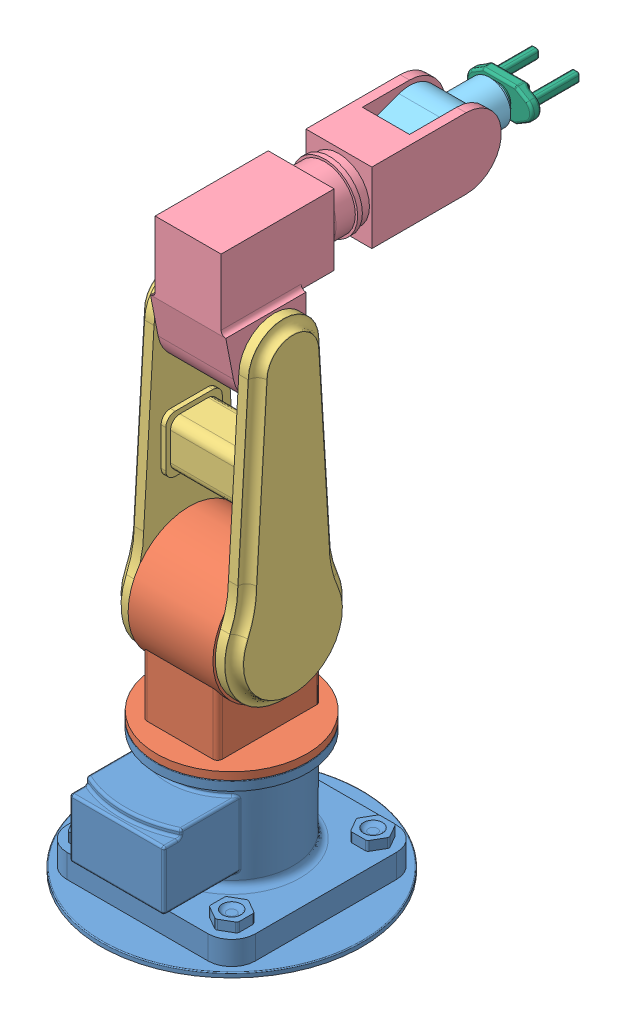
SolidWorks assembly 4DOFmanipulator, configuration 默认. Lengths in mm.
Overall size (555 1216 964.96).
6 component instances, 6 part files, 15 mates.
Components (placement in the parent):
- Base-2: Base [默认] at origin size (555 280 555)
- Link 1-1: Link 1 [默认] at (0 160 0) x (0 0 1) z (-1 0 0) size (320 466 320)
- Link 2-1: Link 2 [默认] at (0 496 0) x (0 0 1) z (-1 0 0) size (250 700 260.14)
- Link 3-1: Link 3 [默认] at (0 1141 92.5448) x (0 0 -1) z (1 0 0) size (595 297.5 160)
- Link 4-1: Link 4 [默认] at (0 1141 -427.4552) x (0 0 -1) z (1 0 0) size (210 130 100)
- Tool-1: Tool [默认] at (0 1141 -547.4552) x (0 0 -1) z (1 0 0) size (140 70 140)
Mates (geometry in assembly coordinates):
- 同心1: concentric anti-aligned: cylinder of Base-2 through (0 80 0) axis (0 1 0) radius 100; cylinder of Link 1-1 through (0 280 0) axis (0 -1 0) radius 100
- 重合2: coincident anti-aligned: plane of Base-2 through (0 280 0) normal (0 1 0); plane of Link 1-1 through (0 280 0) normal (0 -1 0)
- 同心2: concentric aligned: cylinder of Link 1-1 through (-90 496 0) axis (1 0 0) radius 75; cylinder of Link 2-1 through (-90 496 0) axis (1 0 0) radius 75
- 重合3: coincident anti-aligned: plane of Link 1-1 through (90 496 0) normal (1 0 0); plane of Link 2-1 through (90 496 0) normal (-1 0 0)
- 同心4: concentric anti-aligned: cylinder of Link 2-1 through (-90 996 0) axis (1 0 0) radius 50; cylinder of Link 3-1 through (80 996 0) axis (-1 0 0) radius 50
- 重合7: coincident anti-aligned: plane of Link 2-1 through (80 496 0) normal (-1 0 0); plane of Link 3-1 through (80 996 0) normal (1 0 0)
- 同心5: concentric aligned: cylinder of Link 3-1 through (80.002 1141 -427.4552) axis (-1 0 0) radius 50; cylinder of Link 4-1 through (50 1141 -427.4552) axis (-1 0 0) radius 50
- 重合5: coincident anti-aligned: plane of Link 3-1 through (50 1141 -427.4552) normal (-1 0 0); plane of Link 4-1 through (50 1141 -427.4552) normal (1 0 0)
- 平行1: parallel aligned: plane of Base-2 through (100 230 244) normal (1 0 0); plane of Link 1-1 through (80 626.002 -110) normal (1 0 0)
- 平行2: parallel aligned: plane of Link 1-1 through (80 626.002 110) normal (0 0 1); plane of Link 2-1 through (-130.002 716 50) normal (0 0 1)
- 平行3: parallel aligned: plane of Base-2 through (0 0 244) normal (0 0 1); plane of Link 3-1 through (0 1141 92.5448) normal (0 0 1)
- 平行4: parallel aligned: plane of Link 2-1 through (-130.002 816 -50) normal (0 0 -1); plane of Link 4-1 through (0 1141 -547.4552) normal (0 0 -1)
- 重合6: coincident anti-aligned: plane of Link 4-1 through (0 1141 -547.4552) normal (0 0 -1); plane of Tool-1 through (0 1141 -547.4552) normal (0 0 1)
- 同心6: concentric aligned: cylinder of Link 4-1 through (0 1141 -557.4552) axis (0 0 1) radius 25; cylinder of Tool-1 through (0 1141 -567.4552) axis (0 0 1) radius 25
- 平行5: parallel aligned: plane of Link 3-1 through (70 1216 -427.4552) normal (0 1 0); plane of Tool-1 through (35 1176 -587.4552) normal (0 1 0)
